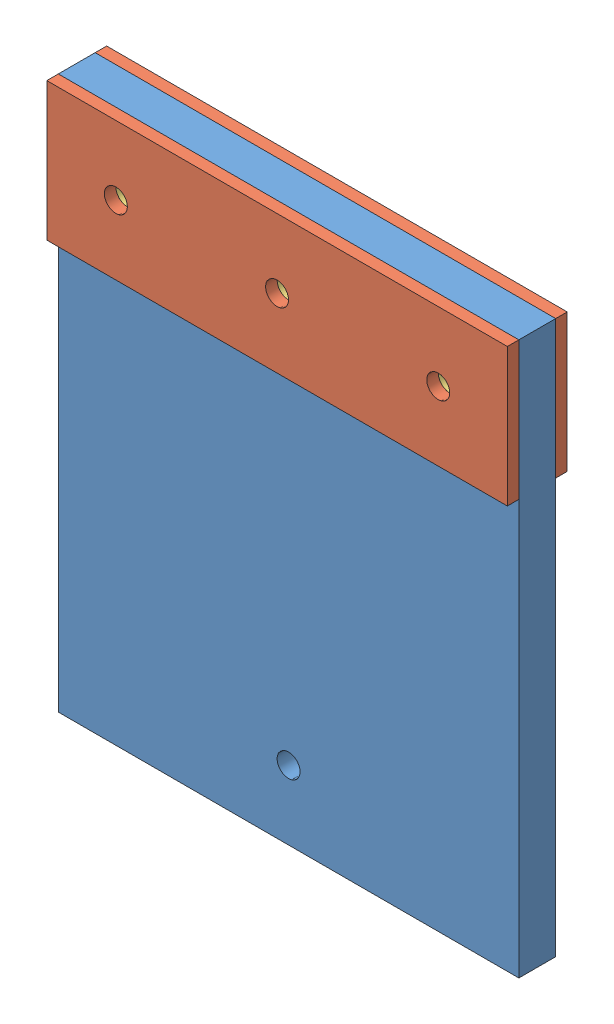
SolidWorks assembly Unsupported Pullthrough Test, configuration Default. Lengths in mm.
Overall size (127 152.4 16.51).
6 component instances, 3 part files, 11 mates.
Components (placement in the parent):
- Carbon Coupon-1: Carbon Coupon [Default] at (30.6326 45.1315 154.2043) size (127 152.4 10.16)
- Part21^Unsupported Pullthrough Test-1: Part21^Unsupported Pullthrough Test [Default] at (30.6326 45.1315 164.3643) size (127 38.1 3.17) (virtual)
- Part21^Unsupported Pullthrough Test-2: Part21^Unsupported Pullthrough Test [Default] at (30.6326 45.1315 151.0293) size (127 38.1 3.17) (virtual)
- Insert-1: Insert [Default] at (49.6826 178.4815 154.2043) x (-0.923728 -0.383049 0) z (-0.383049 0.923728 0) size (12.7 10.16 12.7)
- Insert-2: Insert [Default] at (94.1326 178.4815 154.2043) x (-0.923728 -0.383049 0) z (-0.383049 0.923728 0) size (12.7 10.16 12.7)
- Insert-3: Insert [Default] at (138.5826 178.4815 154.2043) x (-0.923728 -0.383049 0) z (-0.383049 0.923728 0) size (12.7 10.16 12.7)
Mates (geometry in assembly coordinates):
- InPlace1: in place: plane of Carbon Coupon-1 through (30.6326 45.1315 164.3643) normal (0 0 1); plane of ? through (0 0 164.3643) normal (0 0 1); moOrthogonalPlaneRef_w of Carbon Coupon-1 through (30.6326 45.1315 164.3643) normal (0 0 1); plane of ? through (0 0 164.3643) normal (0 1 0); plane of Carbon Coupon-1 through (30.6326 45.1315 164.3643) normal (0 0 1); plane of ? through (0 0 164.3643) normal (1 0 0); plane of Carbon Coupon-1 through (30.6326 45.1315 164.3643) normal (0 0 1); unknown of Part21^Unsupported Pullthrough Test-1
- Coincident1: coincident aligned: plane of ?; plane of ?
- Coincident2: coincident aligned: moOrthogonalPlaneRef_w of Carbon Coupon-1 through (30.6326 45.1315 164.3643) normal (0 1 0); plane of Part20^Assem2-1 through (30.6326 45.1315 164.3643) normal (0 1 0)
- Coincident3: coincident anti-aligned: moOrthogonalPlaneRef_w of Carbon Coupon-1 through (30.6326 45.1315 164.3643) normal (-1 0 0); plane of Part20^Assem2-1 through (30.6326 45.1315 164.3643) normal (1 0 0)
- InPlace2: in place: plane of Carbon Coupon-1 through (30.6326 45.1315 164.3643) normal (0 0 1); plane of ? through (0 0 164.3643) normal (0 0 1); plane of Carbon Coupon-1 through (30.6326 45.1315 164.3643) normal (0 0 1); plane of ? through (0 0 164.3643) normal (0 1 0); plane of Carbon Coupon-1 through (30.6326 45.1315 164.3643) normal (0 0 1); plane of ? through (0 0 164.3643) normal (1 0 0); plane of Carbon Coupon-1 through (30.6326 45.1315 164.3643) normal (0 0 1); unknown of Part21^Unsupported Pullthrough Test-1
- Coincident4: coincident aligned: plane of ?; plane of ?
- Coincident5: coincident aligned: moOrthogonalPlaneRef_w of Carbon Coupon-1 through (30.6326 45.1315 164.3643) normal (0 1 0); plane of Part21^Assem2-1 through (30.6326 45.1315 164.3643) normal (0 1 0)
- Coincident6: coincident anti-aligned: moOrthogonalPlaneRef_w of Carbon Coupon-1 through (30.6326 45.1315 164.3643) normal (-1 0 0); plane of Part21^Assem2-1 through (30.6326 45.1315 164.3643) normal (1 0 0)
- Coincident1: coincident aligned: circle of Part21^Unsupported Pullthrough Test-1; circle of Insert-1
- Coincident2: coincident aligned: circle of Part21^Unsupported Pullthrough Test-1; circle of Insert-2
- Coincident3: coincident aligned: circle of Part21^Unsupported Pullthrough Test-1; circle of Insert-3
